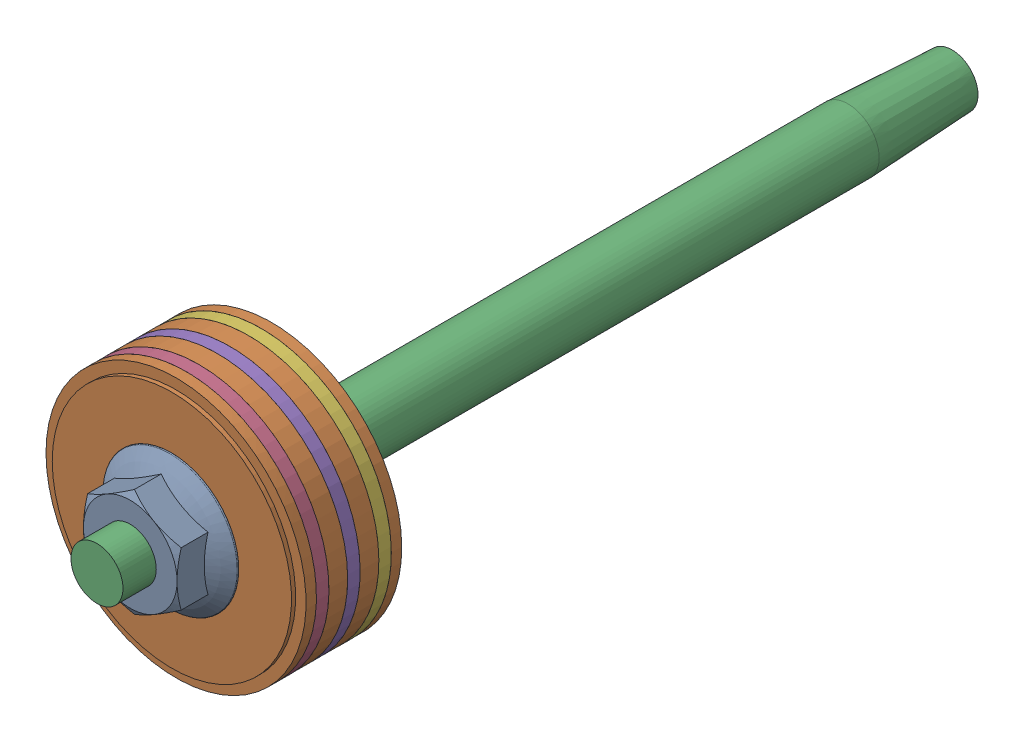
SolidWorks assembly pistonassemble, configuration 默认. Lengths in mm.
Overall size (155.26 155.26 411).
6 component instances, 4 part files, 10 mates.
Components (placement in the parent):
- pistonrodnut-1: pistonrodnut [默认] at (-15.1179 3.2651 0) size (64.9 64.9 20)
- LP-piston-1: LP-piston [默认] at (-15.1179 3.2651 0) x (-0.165861 0.986149 0) z (-0.986149 -0.165861 0) size (125 50 125)
- pistonrod-1: pistonrod [默认] at (-15.1179 3.2651 -169.5) size (30 30 411)
- LP-pistonring-1: LP-pistonring [默认] at (-15.1179 3.2651 -7) x (1 0 0) z (0 1 0) size (125 6 125)
- LP-pistonring-2: LP-pistonring [默认] at (-15.1179 3.2651 -22) x (0.987351 0.158553 0) z (-0.158553 0.987351 0) size (125 6 125)
- LP-pistonring-3: LP-pistonring [默认] at (-15.1179 3.2651 -37) x (0.959125 0.282984 0) z (-0.282984 0.959125 0) size (125 6 125)
Mates (geometry in assembly coordinates):
- 同心1: concentric anti-aligned: cylinder of 低压缸活塞-1 through (-15.1179 3.2651 0) axis (0 0 -1) radius 12.5; cylinder of 活塞杆-1 through (-15.1179 3.2651 -50) axis (0 0 1) radius 12.5
- 重合1: coincident anti-aligned: plane of 低压缸活塞-1 through (-15.1179 3.2651 -50) normal (0 0 -1); plane of 活塞杆-1 through (-15.1179 3.2651 -50) normal (0 0 1)
- 同心2: concentric aligned: cylinder of rod nut-1 through (-15.1179 3.2651 0) axis (0 0 1) radius 12.5; cylinder of 活塞杆-1 through (-15.1179 3.2651 -50) axis (0 0 1) radius 12.5
- 重合2: coincident anti-aligned: plane of rod nut-1 through (-15.1179 3.2651 0) normal (0 0 -1); plane of 低压缸活塞-1 through (-15.1179 3.2651 0) normal (0 0 1)
- 同心3: concentric anti-aligned: cylinder of LP-piston-1 through (-15.1179 3.2651 -7) axis (0 0 -1) radius 57.5; cylinder of LP-pistonring-1 through (-15.1179 3.2651 -13) axis (0 0 1) radius 57.5
- 重合3: coincident anti-aligned: plane of LP-piston-1 through (-15.1179 3.2651 -7) normal (0 0 -1); plane of LP-pistonring-1 through (-15.1179 3.2651 -7) normal (0 0 1)
- 同心4: concentric anti-aligned: cylinder of LP-piston-1 through (-15.1179 3.2651 -7) axis (0 0 -1) radius 57.5; cylinder of LP-pistonring-2 through (-15.1179 3.2651 -28) axis (0 0 1) radius 57.5
- 重合4: coincident anti-aligned: plane of LP-piston-1 through (-15.1179 3.2651 -22) normal (0 0 -1); plane of LP-pistonring-2 through (-15.1179 3.2651 -22) normal (0 0 1)
- 同心5: concentric anti-aligned: cylinder of LP-piston-1 through (-15.1179 3.2651 -7) axis (0 0 -1) radius 57.5; cylinder of LP-pistonring-3 through (-15.1179 3.2651 -43) axis (0 0 1) radius 57.5
- 重合5: coincident anti-aligned: plane of LP-piston-1 through (-15.1179 3.2651 -37) normal (0 0 -1); plane of LP-pistonring-3 through (-15.1179 3.2651 -37) normal (0 0 1)
